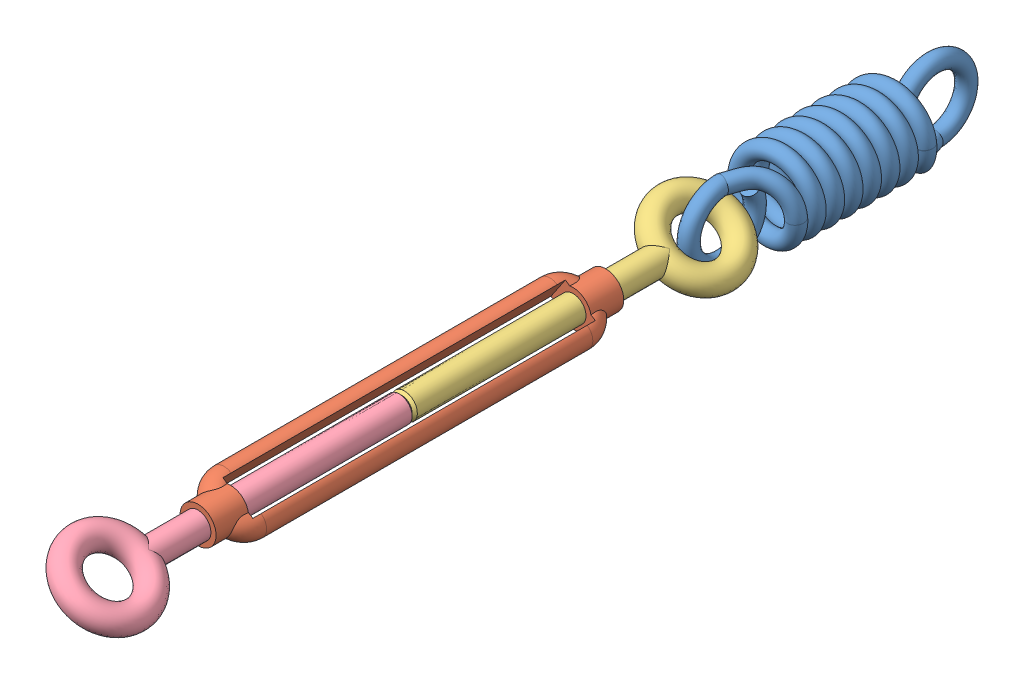
SolidWorks assembly Systeme tension, configuration Default. Lengths in mm.
Overall size (18.83 16.19 176.97).
5 component instances, 4 part files, 1 mates.
Components (placement in the parent):
- Ressort-1: Ressort [Default] at (41.4989 37.8914 -5.9626) size (16.19 16.19 57)
- Tendeur-1: Tendeur [Default] at (41.4989 37.8914 101.8123) x (0.560693 0.828024 0) z (-0.828024 0.560693 0) size (7 132 18)
  - 4246a05zcmu_01-1: 4246a05zcmu_01 [Default] at origin size (7 79 12)
  - 4246a05zcmu_02-1: 4246a05zcmu_02 [Default] at origin size (5 66 18)
  - 4246a05zcmu_03-1: 4246a05zcmu_03 [Default] at origin size (5 66 18)
Mates (geometry in assembly coordinates):
- Coaxiale1: concentric anti-aligned: line of Ressort-1 through (41.4989 37.8914 50.6874) axis (0 0 -1); cylinder of Tendeur-1/4246a05zcmu_02-1 through (41.4989 37.8914 76.5623) axis (0 0 1) radius 2.5
